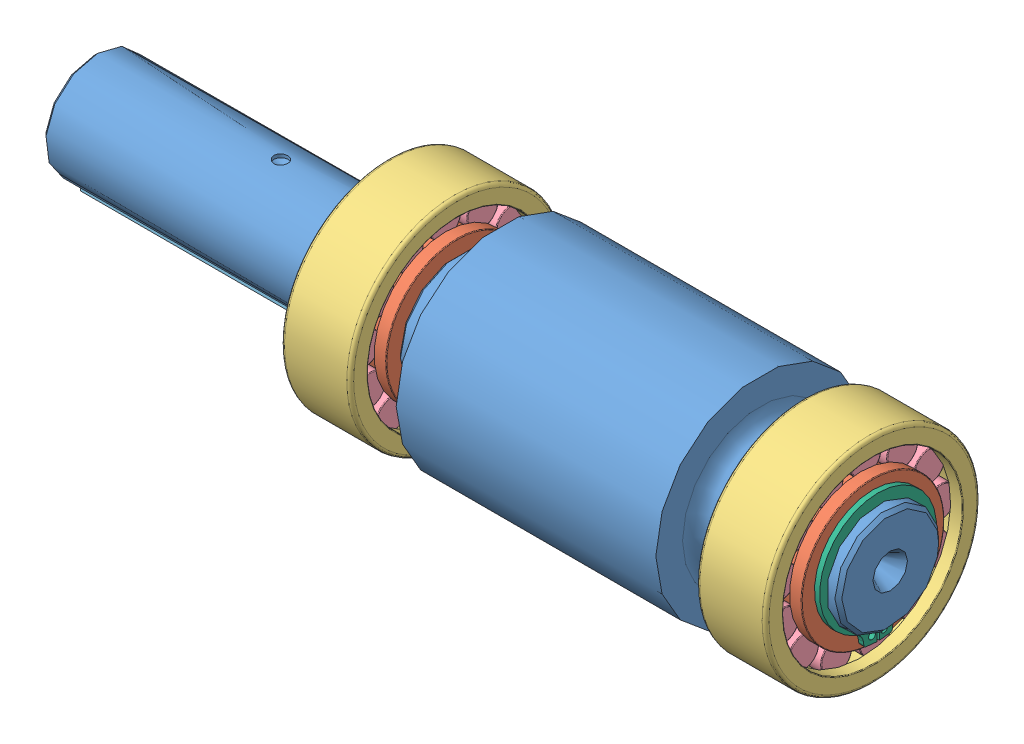
SolidWorks assembly podsklop_v1, configuration Default. Lengths in mm.
Overall size (230 81.89 81.89).
12 component instances, 7 part files, 11 mates.
Components (placement in the parent):
- Vratilo_1-1: Vratilo_1 [Default] at (-103.4374 153.1627 192.3391) size (230 63.09 60.45)
- skf_bearing_nup_2206_ecp_2-1: skf_bearing_nup_2206_ecp_2 [Default] at (-18.4374 153.1627 192.3391) size (20 62 62)
  - skf_bearing_nup_2206_ecp_2_01-1: skf_bearing_nup_2206_ecp_2_01 [Default] at origin size (20 41.2 41.2)
  - skf_bearing_nup_2206_ecp_2_02-1: skf_bearing_nup_2206_ecp_2_02 [Default] at origin size (20 62 62)
  - skf_bearing_nup_2206_ecp_2_03-1: skf_bearing_nup_2206_ecp_2_03 [Default] at origin size (13 54.82 55.16)
- skf_bearing_nup_2206_ecp_2-2: skf_bearing_nup_2206_ecp_2 [Default] at (101.5626 153.1627 192.3391) x (1 0 0) z (0 -0.407591 0.913164) size (20 62 62)
  - skf_bearing_nup_2206_ecp_2_01-1: skf_bearing_nup_2206_ecp_2_01 [Default] at origin size (20 41.2 41.2)
  - skf_bearing_nup_2206_ecp_2_02-1: skf_bearing_nup_2206_ecp_2_02 [Default] at origin size (20 62 62)
  - skf_bearing_nup_2206_ecp_2_03-1: skf_bearing_nup_2206_ecp_2_03 [Default] at origin size (13 54.82 55.16)
- pero-1: pero [Default] at (-73.4374 142.2627 192.3391) x (-1 0 0) z (0 -1 0) size (60 8 7)
- circlip for shafts normal_din-3: circlip for shafts normal_din [Circlip DIN 471 - 30 x 1.5] at (121.5626 153.1627 192.3391) x (0 0 1) z (-1 0 0) size (33.78 37.1 1.5)
- countersunk flat head cross recess screw_din-4: countersunk flat head cross recess screw_din [DIN EN ISO 7046-1 - M3 x 10 - Z - 10N] at (-73.4374 135.2627 192.3391) x (0 1 0) z (-0.99395 0 0.109831) size (10 5.5 5.5)
Mates (geometry in assembly coordinates):
- Concentric1: concentric anti-aligned: cylinder of Vratilo_1-1 through (126.5626 153.1627 192.3391) axis (1 0 0) radius 15; cylinder of skf_bearing_nup_2206_ecp_2-2/skf_bearing_nup_2206_ecp_2_01-1 through (111.7626 153.1627 192.3391) axis (-1 0 0) radius 15
- Coincident1: coincident anti-aligned: plane of Vratilo_1-1 through (101.5626 170.6627 192.3391) normal (1 0 0); plane of skf_bearing_nup_2206_ecp_2-2/skf_bearing_nup_2206_ecp_2_01-1 through (101.5626 169.7823 199.7572) normal (-1 0 0)
- Concentric2: concentric anti-aligned: cylinder of Vratilo_1-1 through (126.5626 153.1627 192.3391) axis (1 0 0) radius 15; cylinder of skf_bearing_nup_2206_ecp_2-1/skf_bearing_nup_2206_ecp_2_01-1 through (-8.2374 153.1627 192.3391) axis (-1 0 0) radius 15
- Coincident2: coincident anti-aligned: plane of Vratilo_1-1 through (1.5626 168.9627 192.3391) normal (-1 0 0); plane of skf_bearing_nup_2206_ecp_2-1/skf_bearing_nup_2206_ecp_2_01-1 through (1.5626 171.1627 192.3391) normal (1 0 0)
- Concentric4: concentric aligned: circle of Vratilo_1-1; circle of pero-1
- Coincident3: coincident anti-aligned: plane of Vratilo_1-1 through (-103.4374 142.2627 192.3391) normal (0 -1 0); plane of pero-1 through (-73.4374 142.2627 192.3391) normal (0 1 0)
- Parallel2: parallel anti-aligned: plane of pero-1 through (-43.4374 135.2627 196.3391) normal (1 0 0); plane of Vratilo_1-1 through (-103.4374 153.1627 192.3391) normal (-1 0 0)
- Concentric7: concentric anti-aligned: cylinder of Vratilo_1-1 through (126.5626 153.1627 192.3391) axis (1 0 0) radius 14.3; cylinder of circlip for shafts normal_din-3 through (123.0626 153.1627 192.3391) axis (-1 0 0) radius 14.3
- Coincident10: coincident anti-aligned: plane of Vratilo_1-1 through (121.5626 167.4627 192.3391) normal (1 0 0); plane of circlip for shafts normal_din-3 through (121.5626 153.1627 192.3391) normal (-1 0 0)
- Concentric8: concentric aligned: circle of pero-1; circle of countersunk flat head cross recess screw_din-4
- Coincident11: coincident aligned: cone of pero-1 through (-73.4374 135.2627 192.3391) axis (0 1 0); cone of countersunk flat head cross recess screw_din-4 through (-73.4374 135.6627 192.3391) axis (0 1 0)
